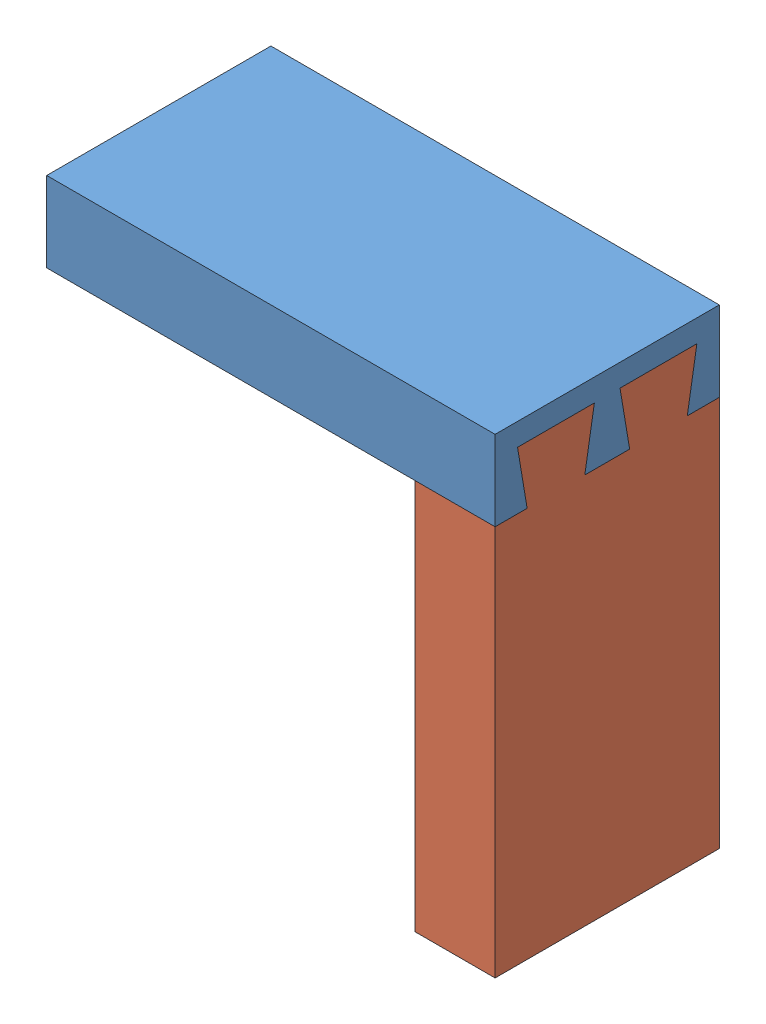
SolidWorks assembly LAPPED DOVETAIL, configuration Default. Lengths in mm.
Overall size (140 147 70).
2 component instances, 2 part files, 3 mates.
Components (placement in the parent):
- PINS-1: PINS [Default] at (-139.8799 -10.108 82.5018) size (140 25 70)
- TAILS-1: TAILS [Default] at (-24.8799 -132.108 82.5018) size (25 140 70)
Mates (geometry in assembly coordinates):
- Coincident1: coincident aligned: plane of PINS-1 through (-139.8799 14.892 82.5018) normal (0 0 1); plane of TAILS-1 through (0.1201 -132.108 82.5018) normal (0 0 1)
- Coincident2: coincident aligned: plane of PINS-1 through (0.1201 14.892 82.5018) normal (1 0 0); plane of TAILS-1 through (0.1201 7.892 82.5018) normal (1 0 0)
- Coincident3: coincident anti-aligned: plane of PINS-1 through (-24.8799 7.892 75.5018) normal (0 -1 0); plane of TAILS-1 through (0.1201 7.892 82.5018) normal (0 1 0)
